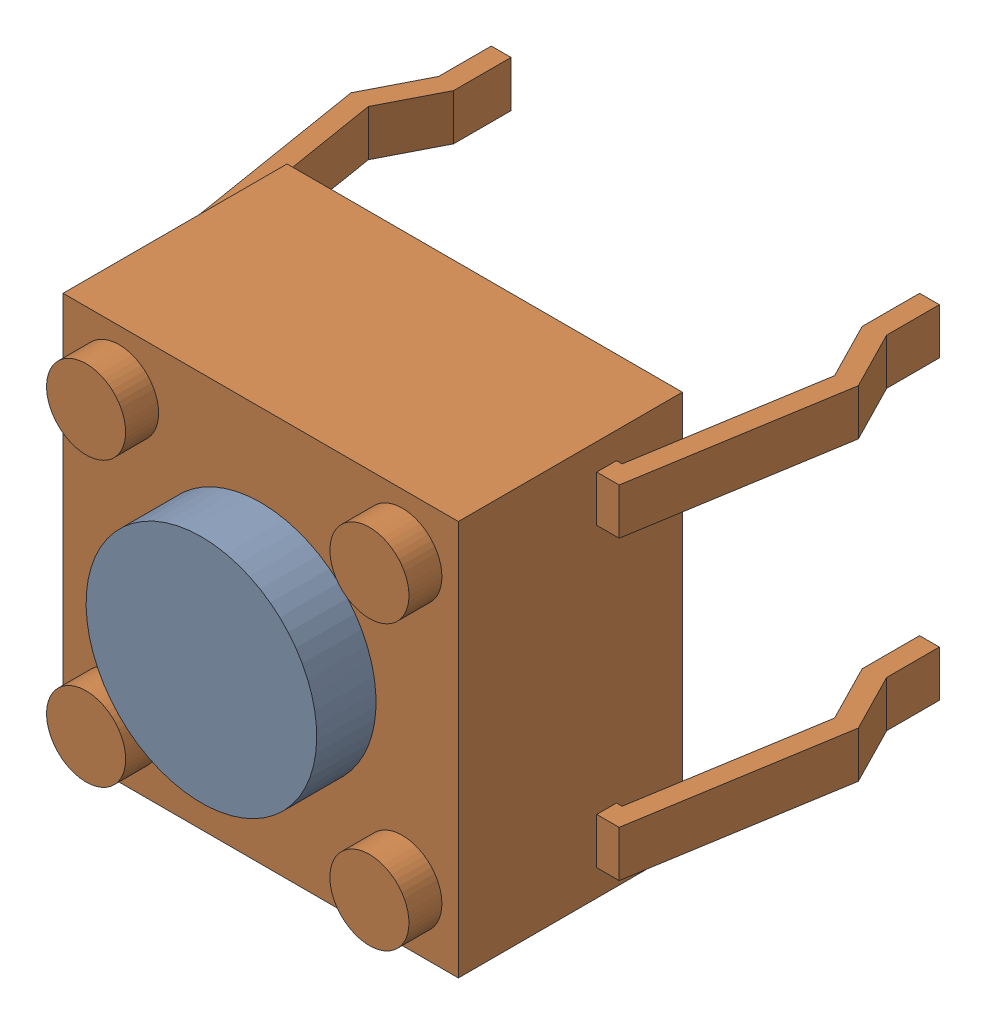
SolidWorks assembly Kanaloa_v2.0.0_Loko_2, configuration Default. Lengths in mm.
Overall size (7.7 6 7.8).
3 component instances, 2 part files, 0 mates.
Components (placement in the parent):
- OMRON-B3F_1000-1: OMRON-B3F_1000 [Default] at (103.6682 75.7682 0) x (1 0 0) z (0 -1 0) size (7.7 7.8 6)
  - OMRON-B3F_1000_B3F_1000_BUTTON-1: OMRON-B3F_1000_B3F_1000_BUTTON [Default] at (0 4.3 0) x (-1 0 0) z (0 0 -1) size (3.5 1 3.5)
  - OMRON-B3F_1000_B3F_1000_BASE-1: OMRON-B3F_1000_B3F_1000_BASE [Default] at origin size (7.7 7.4 6)
